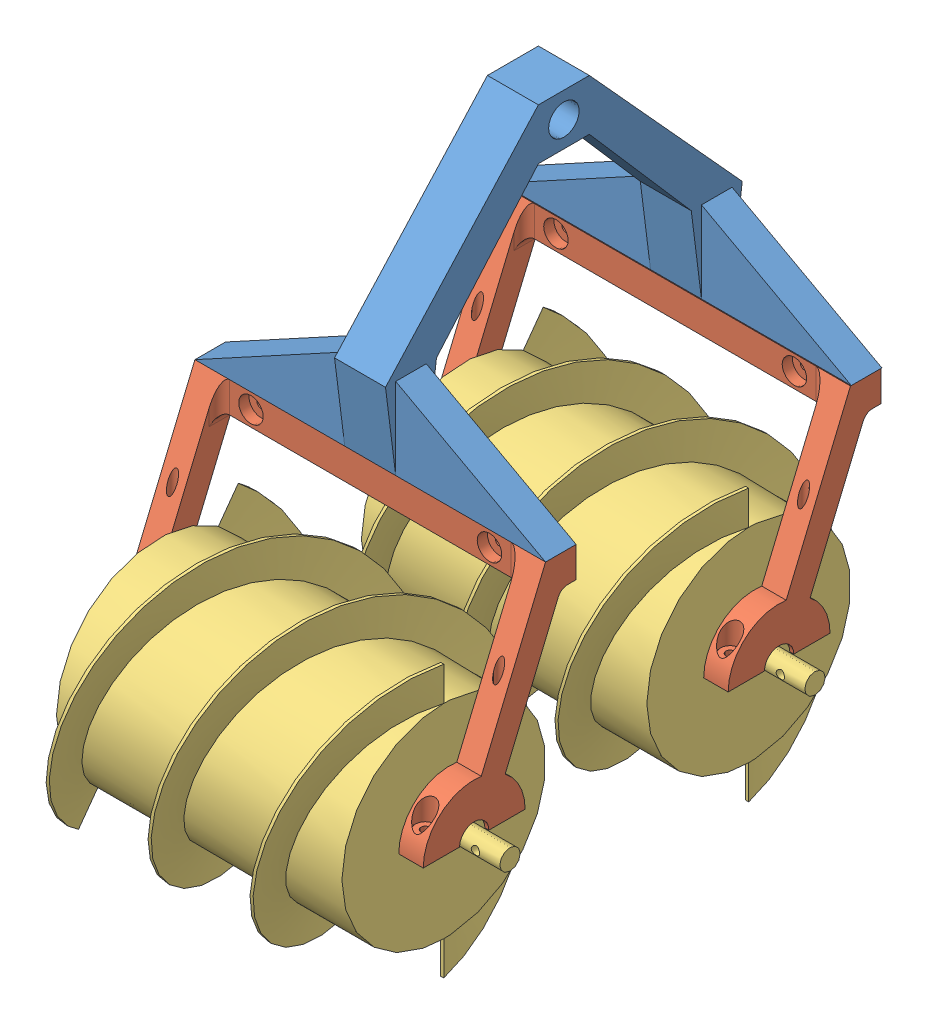
SolidWorks assembly Assem3, configuration Default. Lengths in mm.
Overall size (189.58 289.46 282.93).
7 component instances, 3 part files, 5 mates.
Components (placement in the parent):
- Rocker_0.2-1: Rocker_0.2 [Default] at (90.7291 81.5764 127.5436) size (172 122.5 175)
- Right_Side_Wheel-1: Right_Side_Wheel [Default] at (-44.7546 -109.1572 354.9679) x (0 0 -1) z (1 0 0) size (133.34 166.96 189.58)
  - GSL_Feet_Right_GSL12-1: GSL_Feet_Right_GSL12 [Default] at (92.4243 183.2337 135.4838) size (133.3 166.65 172)
  - HGSL2_CC-1: HGSL2_CC [Default] at (34.9243 90.7337 66.5638) size (133.34 133.91 174.84)
- Right_Side_Wheel-2: Right_Side_Wheel [Default] at (-44.7546 -109.1572 205.3767) x (0 0 -1) z (1 0 0) size (133.34 166.96 189.58)
  - GSL_Feet_Right_GSL12-1: GSL_Feet_Right_GSL12 [Default] at (92.4243 183.2337 135.4838) size (133.3 166.65 172)
  - HGSL2_CC-1: HGSL2_CC [Default] at (34.9243 90.7337 66.5638) size (133.34 133.91 174.84)
Mates (geometry in assembly coordinates):
- Coincident4: coincident: plane of Rocker_0.2-1 through (90.7291 81.5764 277.5436) normal (0 -1 0); plane of Right_Side_Wheel-1/GSL_Feet_Right_GSL12-1 through (176.7291 81.5764 270.0436) normal (0 1 0)
- Coincident5: coincident: line of Rocker_0.2-1 through (176.7291 81.5764 285.0436) axis (0 0 -1); line of Right_Side_Wheel-1/GSL_Feet_Right_GSL12-1 through (176.7291 81.5764 270.0436) axis (0 0 1)
- Coincident6: coincident: plane of Rocker_0.2-1 through (90.7291 121.5764 285.0436) normal (0 0 1); plane of Right_Side_Wheel-1/GSL_Feet_Right_GSL12-1 through (176.7291 66.5764 285.0436) normal (0 0 1)
- Coincident7: coincident: plane of Rocker_0.2-1 through (90.7291 81.5764 127.5436) normal (0 -1 0); plane of Right_Side_Wheel-2/GSL_Feet_Right_GSL12-1 through (176.7291 81.5764 120.4524) normal (0 1 0)
- Coincident8: coincident: line of Rocker_0.2-1 through (176.7291 81.5764 120.0436) axis (0 0 1); plane of Right_Side_Wheel-2/GSL_Feet_Right_GSL12-1 through (176.7291 74.0764 112.9524) normal (1 0 0)
